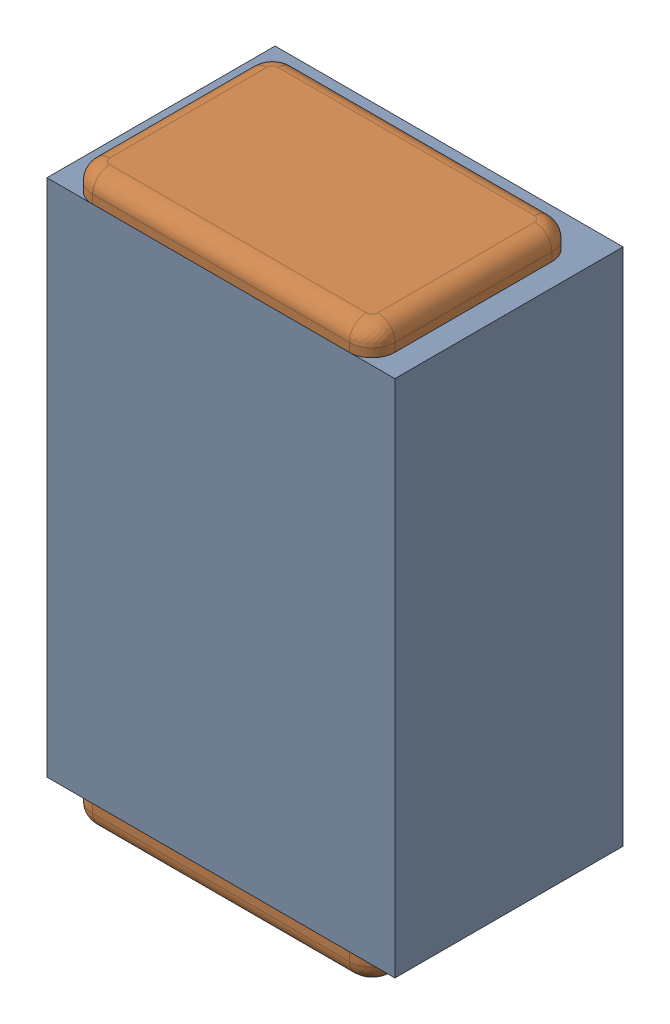
SolidWorks assembly C34, configuration Default. Lengths in mm.
Overall size (0.61 1 0.4).
3 component instances, 2 part files, 0 mates.
Components (placement in the parent):
- 1088881848-1: 1088881848 [Default] at (4.725 31.775 -2.044) size (0.61 0.91 0.4)
  - Extruded-1-1: Extruded-1 [Default] at origin size (0.61 0.91 0.4)
- C0402-1: C0402 [Default] at (4.7251 31.7751 -1.644) x (0 1 0) z (-1 0 0) size (1 0.36 0.54)
